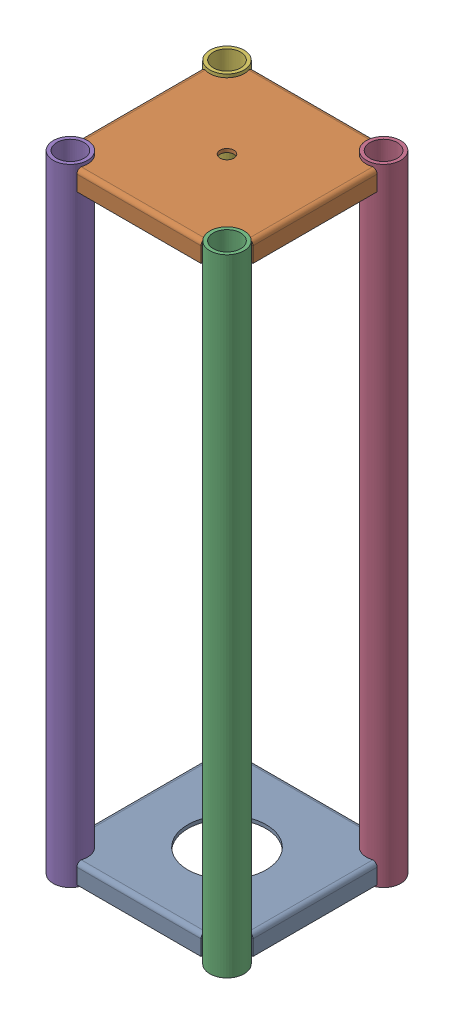
SolidWorks assembly GE-25801, configuration Default. Lengths in mm.
Overall size (185.8 609.6 185.8).
6 component instances, 3 part files, 17 mates.
Components (placement in the parent):
- GE-25801-01-1: GE-25801-01 [Default] at (0 22.225 0) size (171.42 19.05 171.42)
- GE-25801-02-1: GE-25801-02 [Default] at (0 606.425 0) size (171.42 19.05 171.42)
- GE-25801-03-1: GE-25801-03 [Default] at (76.2 0 76.2) size (33.4 609.6 33.4)
- GE-25801-03-2: GE-25801-03 [Default] at (76.2 0 -76.2) size (33.4 609.6 33.4)
- GE-25801-03-3: GE-25801-03 [Default] at (-76.2 0 76.2) size (33.4 609.6 33.4)
- GE-25801-03-4: GE-25801-03 [Default] at (-76.2 0 -76.2) size (33.4 609.6 33.4)
Mates (geometry in assembly coordinates):
- Coincident1: coincident aligned: plane of shortie_m6-01-1 through (0 22.225 0) normal (0 0 1)
- Coincident2: coincident aligned: plane of shortie_m6-01-1 through (0 22.225 0) normal (1 0 0)
- Coincident3: coincident aligned: plane of shortie_m6-01-1 through (0 22.225 85.7123) normal (0 0 1); plane of shortie_m6-02-1 through (0 606.425 85.7123) normal (0 0 1)
- Coincident4: coincident aligned: plane of shortie_m6-01-1 through (85.7123 22.225 0) normal (1 0 0); plane of shortie_m6-02-1 through (85.7123 606.425 0) normal (1 0 0)
- Distance1: distance = 603.25 mm anti-aligned: plane of shortie_m6-02-1 through (76.2 606.425 76.2) normal (0 1 0); plane of shortie_m6-01-1 through (-60.3828 3.175 85.7123) normal (0 -1 0)
- Concentric1: concentric anti-aligned: cylinder of shortie_m6-02-1 through (-76.2 603.0087 76.2) axis (0 1 0) radius 16.7005; cylinder of shortie_m6-03-3 through (-76.2 609.6 76.2) axis (0 -1 0) radius 16.7005
- Distance2: distance = 3.175 mm aligned: plane of shortie_m6-03-3 through (-76.2 609.6 76.2) normal (0 1 0); plane of shortie_m6-02-1 through (76.2 606.425 76.2) normal (0 1 0)
- Concentric2: concentric anti-aligned: cylinder of shortie_m6-02-1 through (76.2 603.0087 76.2) axis (0 1 0) radius 16.7005; cylinder of shortie_m6-03-1 through (76.2 609.6 76.2) axis (0 -1 0) radius 16.7005
- Coincident7: coincident aligned: plane of shortie_m6-03-1 through (76.2 609.6 76.2) normal (0 1 0); plane of shortie_m6-03-3 through (-76.2 609.6 76.2) normal (0 1 0)
- Concentric3: concentric anti-aligned: cylinder of shortie_m6-02-1 through (76.2 603.0087 -76.2) axis (0 1 0) radius 16.7005; cylinder of shortie_m6-03-2 through (76.2 609.6 -76.2) axis (0 -1 0) radius 16.7005
- Coincident8: coincident aligned: plane of shortie_m6-03-1 through (76.2 609.6 76.2) normal (0 1 0); plane of shortie_m6-03-2 through (76.2 609.6 -76.2) normal (0 1 0)
- Concentric4: concentric anti-aligned: line of shortie_m6-02-1 through (-76.2 603.0087 -76.2) axis (0 1 0); axis of shortie_m6-03-4 through (-76.2 609.6 -76.2) axis (0 -1 0)
- Coincident9: coincident aligned: plane of shortie_m6-03-2 through (76.2 609.6 -76.2) normal (0 1 0); plane of shortie_m6-03-4 through (-76.2 609.6 -76.2) normal (0 1 0)
- Coincident10: coincident anti-aligned: plane of shortie_m6-03-1 through (76.2 0 76.2) normal (0 -1 0)
- Coincident11: coincident anti-aligned: plane of shortie_m6-03-3 through (-76.2 0 76.2) normal (0 -1 0)
- Coincident12: coincident anti-aligned: plane of shortie_m6-03-4 through (-76.2 0 -76.2) normal (0 -1 0)
- Coincident13: coincident anti-aligned: plane of shortie_m6-03-2 through (76.2 0 -76.2) normal (0 -1 0)
